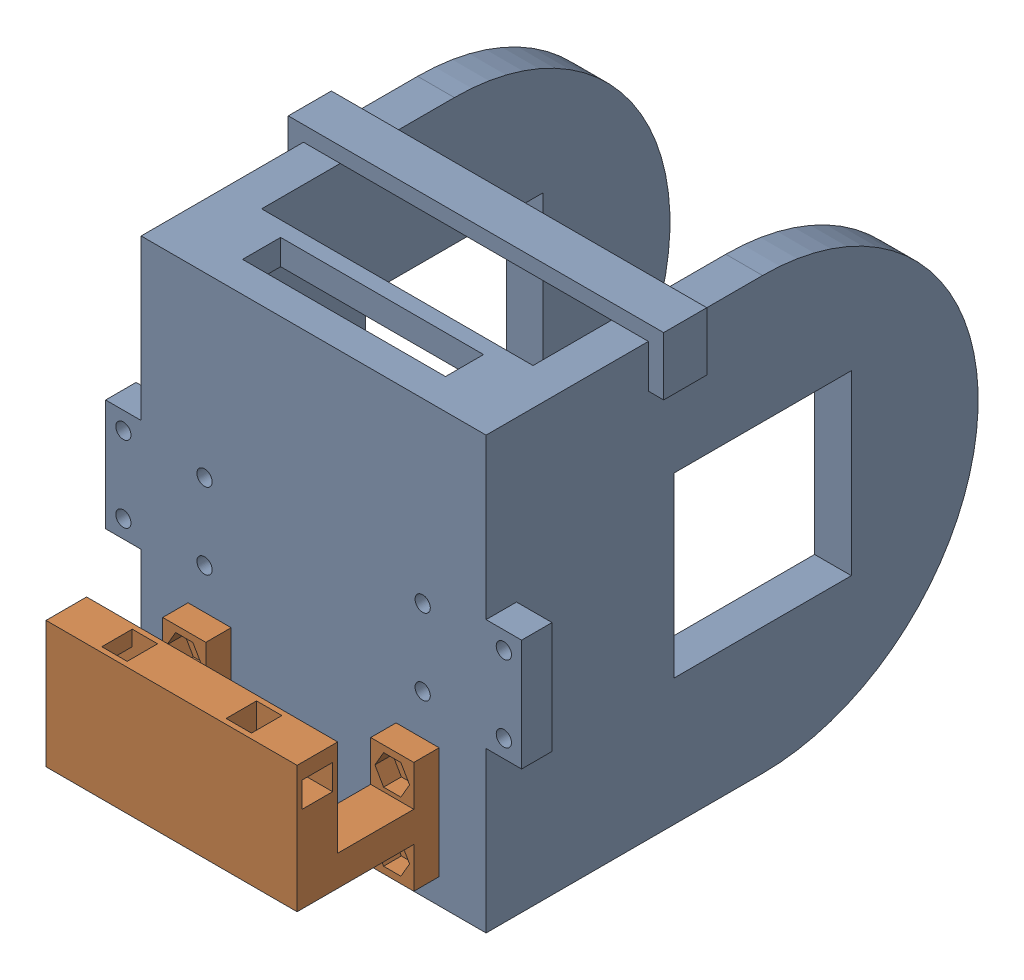
SolidWorks assembly BeltHolderCheck, configuration Default. Lengths in mm.
Overall size (82 88 125).
2 component instances, 2 part files, 5 mates.
Components (placement in the parent):
- Part4^WallsSet_1_2part_V2-1: Part4^WallsSet_1_2part_V2 [Default] at (-48.473 -23.3725 41.4575) size (82 88 97)
- belt holder_V2-1: belt holder_V2 [Default] at (-68.973 -49.8725 41.4575) x (1 0 0) z (0 -1 0) size (49.5 28 33)
Mates (geometry in assembly coordinates):
- Coincident1: coincident: plane of Part4^WallsSet_1_2part_V2-1 through (-48.473 -23.3725 41.4575) normal (0 0 1); plane of belt holder-1 through (-68.973 -49.8725 41.4575) normal (0 0 -1)
- Concentric1: concentric aligned: circle of Part4^WallsSet_1_2part_V2-1; circle of belt holder-1
- Coincident3: coincident: plane of Part4^WallsSet_1_2part_V2-1 through (-48.473 -23.3725 41.4575) normal (0 0 1); plane of belt holder_V2-1 through (-68.973 -49.8725 41.4575) normal (0 0 -1)
- Concentric2: concentric: circle of Part4^WallsSet_1_2part_V2-1; circle of belt holder_V2-1
- Parallel1: parallel aligned: plane of Part4^WallsSet_1_2part_V2-1 through (-82.473 -65.8725 -58.0425) normal (-1 0 0); plane of belt holder_V2-1 through (-73.223 -60.8725 46.4575) normal (-1 0 0)
